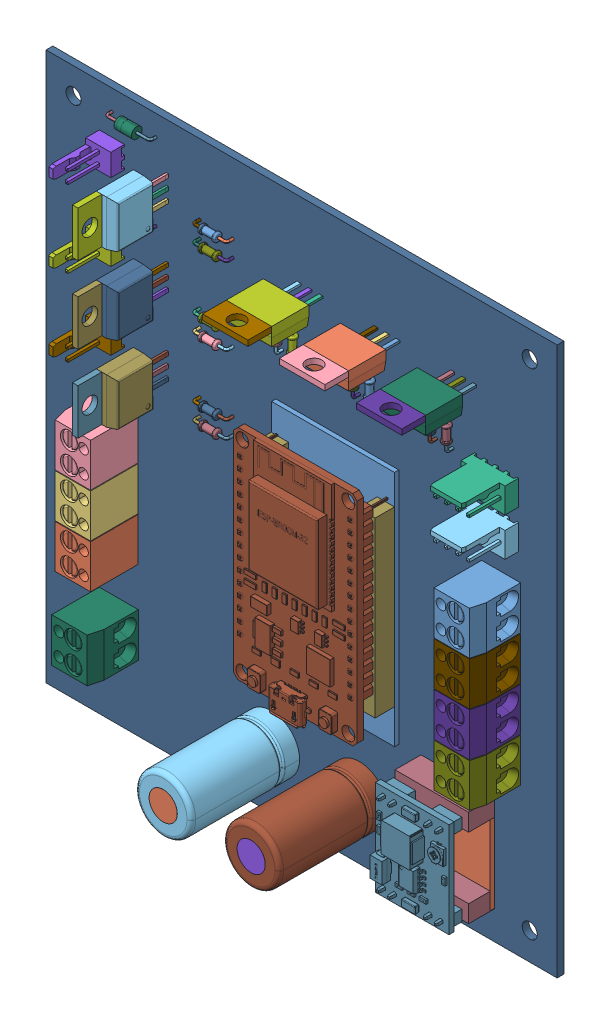
SolidWorks assembly ESP pcb v2 cad, configuration Standard. Lengths in mm.
Overall size (118.09 126.67 29.51).
107 component instances, 104 part files, 12 mates.
Components (placement in the parent):
- PPP5efa1a2bd6d06.stp-1: PPP5efa1a2bd6d06.stp [Standard] at origin size (118.09 126.67 29.51)
  - CAPPRD500W45D1300H2500P001.stp-1: CAPPRD500W45D1300H2500P001.stp [Standard] at (80.01 45.72 1.57) x (0 1 0) z (0 0 1) size (0.45 0.45 2.54)
  - CAPPRD500W45D1300H2500P002.stp-1: CAPPRD500W45D1300H2500P002.stp [Standard] at (80.01 45.72 1.57) x (0 1 0) z (0 0 1) size (6.5 6.5 0.01)
  - CAPPRD500W45D1300H2500P003.stp-1: CAPPRD500W45D1300H2500P003.stp [Standard] at (80.01 45.72 1.57) x (0 1 0) z (0 0 1) size (0.62 5.51 19.3)
  - CAPPRD500W45D1300H2500P004.stp-1: CAPPRD500W45D1300H2500P004.stp [Standard] at (80.01 45.72 1.57) x (0 1 0) z (0 0 1) size (0.62 5.51 3.3)
  - CAPPRD500W45D1300H2500P005.stp-1: CAPPRD500W45D1300H2500P005.stp [Standard] at (80.01 45.72 1.57) x (0 1 0) z (0 0 1) size (13 13 25)
  - CAPPRD500W45D1300H2500P.stp-1: CAPPRD500W45D1300H2500P.stp [Standard] at (80.01 45.72 1.57) x (0 1 0) z (0 0 1) size (0.45 0.45 2.54)
  - CAPPRD500W45D1300H2500P006.stp-1: CAPPRD500W45D1300H2500P006.stp [Standard] at (100.33 45.72 1.57) x (0 1 0) z (0 0 1) size (0.45 0.45 2.54)
  - CAPPRD500W45D1300H2500P007.stp-1: CAPPRD500W45D1300H2500P007.stp [Standard] at (100.33 45.72 1.57) x (0 1 0) z (0 0 1) size (6.5 6.5 0.01)
  - CAPPRD500W45D1300H2500P008.stp-1: CAPPRD500W45D1300H2500P008.stp [Standard] at (100.33 45.72 1.57) x (0 1 0) z (0 0 1) size (0.62 5.51 19.3)
  - CAPPRD500W45D1300H2500P009.stp-1: CAPPRD500W45D1300H2500P009.stp [Standard] at (100.33 45.72 1.57) x (0 1 0) z (0 0 1) size (0.62 5.51 3.3)
  - CAPPRD500W45D1300H2500P010.stp-1: CAPPRD500W45D1300H2500P010.stp [Standard] at (100.33 45.72 1.57) x (0 1 0) z (0 0 1) size (13 13 25)
  - CAPPRD500W45D1300H2500P011.stp-1: CAPPRD500W45D1300H2500P011.stp [Standard] at (100.33 45.72 1.57) x (0 1 0) z (0 0 1) size (0.45 0.45 2.54)
  - DIOAD1016W58L400D250P.stp-1: DIOAD1016W58L400D250P.stp [Standard] at (48.26 153.67 1.57) size (3.37 0.58 4.18)
  - DIOAD1016W58L400D250P001.stp-1: DIOAD1016W58L400D250P001.stp [Standard] at (48.26 153.67 1.57) size (3.37 0.58 4.18)
  - DIOAD1016W58L400D250P002.stp-1: DIOAD1016W58L400D250P002.stp [Standard] at (48.26 153.67 1.57) size (4 2.51 2.51)
  - DIOAD1016W58L400D250P003.stp-1: DIOAD1016W58L400D250P003.stp [Standard] at (48.26 135.89 1.57) size (3.37 0.58 4.18)
  - DIOAD1016W58L400D250P004.stp-1: DIOAD1016W58L400D250P004.stp [Standard] at (48.26 135.89 1.57) size (3.37 0.58 4.18)
  - DIOAD1016W58L400D250P005.stp-1: DIOAD1016W58L400D250P005.stp [Standard] at (48.26 135.89 1.57) size (4 2.51 2.51)
  - Component_1.stp-1: Component_1.stp [Standard] at (95.25 87.63 1.57) x (-1 0 0) z (0 0 1) size (28.4 54.9 1)
  - Component_2.stp-1: Component_2.stp [Standard] at (123.19 49.53 1.57) x (0 1 0) z (0 0 1) size (22.1 16.76 1)
  - TO254P1051X465X1957-3P.stp-1: TO254P1051X465X1957-3P.stp [Standard] at (53.34 144.78 1.57) x (0 1 0) z (0 0 1) size (0.9 0.49 5.51)
  - TO254P1051X465X1957-3P002.stp-1: TO254P1051X465X1957-3P002.stp [Standard] at (53.34 144.78 1.57) x (0 1 0) z (0 0 1) size (0.9 0.49 5.51)
  - TO254P1051X465X1957-3P004.stp-1: TO254P1051X465X1957-3P004.stp [Standard] at (53.34 144.78 1.57) x (0 1 0) z (0 0 1) size (13.23 6.47 11.63)
  - TO254P1051X465X1957-3P001.stp-1: TO254P1051X465X1957-3P001.stp [Standard] at (53.34 144.78 1.57) x (0 1 0) z (0 0 1) size (0.9 0.49 5.51)
  - TO254P1051X465X1957-3P003.stp-1: TO254P1051X465X1957-3P003.stp [Standard] at (53.34 144.78 1.57) x (0 1 0) z (0 0 1) size (10.51 1.27 5.5)
  - TO254P1051X465X1957-3P005.stp-1: TO254P1051X465X1957-3P005.stp [Standard] at (53.34 127 1.57) x (0 1 0) z (0 0 1) size (0.9 0.49 5.51)
  - TO254P1051X465X1957-3P006.stp-1: TO254P1051X465X1957-3P006.stp [Standard] at (53.34 127 1.57) x (0 1 0) z (0 0 1) size (0.9 0.49 5.51)
  - TO254P1051X465X1957-3P007.stp-1: TO254P1051X465X1957-3P007.stp [Standard] at (53.34 127 1.57) x (0 1 0) z (0 0 1) size (13.23 6.47 11.63)
  - TO254P1051X465X1957-3P008.stp-1: TO254P1051X465X1957-3P008.stp [Standard] at (53.34 127 1.57) x (0 1 0) z (0 0 1) size (0.9 0.49 5.51)
  - TO254P1051X465X1957-3P009.stp-1: TO254P1051X465X1957-3P009.stp [Standard] at (53.34 127 1.57) x (0 1 0) z (0 0 1) size (10.51 1.27 5.5)
  - TO254P1051X465X1957-3P010.stp-1: TO254P1051X465X1957-3P010.stp [Standard] at (124.46 143.51 1.57) size (0.9 0.49 5.51)
  - TO254P1051X465X1957-3P011.stp-1: TO254P1051X465X1957-3P011.stp [Standard] at (124.46 143.51 1.57) size (0.9 0.49 5.51)
  - TO254P1051X465X1957-3P012.stp-1: TO254P1051X465X1957-3P012.stp [Standard] at (124.46 143.51 1.57) size (13.23 6.47 11.63)
  - TO254P1051X465X1957-3P013.stp-1: TO254P1051X465X1957-3P013.stp [Standard] at (124.46 143.51 1.57) size (0.9 0.49 5.51)
  - TO254P1051X465X1957-3P014.stp-1: TO254P1051X465X1957-3P014.stp [Standard] at (124.46 143.51 1.57) size (10.51 1.27 5.5)
  - TO254P1051X465X1957-3P015.stp-1: TO254P1051X465X1957-3P015.stp [Standard] at (106.68 143.51 1.57) size (0.9 0.49 5.51)
  - TO254P1051X465X1957-3P016.stp-1: TO254P1051X465X1957-3P016.stp [Standard] at (106.68 143.51 1.57) size (0.9 0.49 5.51)
  - TO254P1051X465X1957-3P017.stp-1: TO254P1051X465X1957-3P017.stp [Standard] at (106.68 143.51 1.57) size (13.23 6.47 11.63)
  - TO254P1051X465X1957-3P018.stp-1: TO254P1051X465X1957-3P018.stp [Standard] at (106.68 143.51 1.57) size (0.9 0.49 5.51)
  - TO254P1051X465X1957-3P019.stp-1: TO254P1051X465X1957-3P019.stp [Standard] at (106.68 143.51 1.57) size (10.51 1.27 5.5)
  - TO254P1051X465X1957-3P020.stp-1: TO254P1051X465X1957-3P020.stp [Standard] at (88.9 143.51 1.57) size (0.9 0.49 5.51)
  - TO254P1051X465X1957-3P021.stp-1: TO254P1051X465X1957-3P021.stp [Standard] at (88.9 143.51 1.57) size (0.9 0.49 5.51)
  - TO254P1051X465X1957-3P022.stp-1: TO254P1051X465X1957-3P022.stp [Standard] at (88.9 143.51 1.57) size (13.23 6.47 11.63)
  - TO254P1051X465X1957-3P023.stp-1: TO254P1051X465X1957-3P023.stp [Standard] at (88.9 143.51 1.57) size (0.9 0.49 5.51)
  - TO254P1051X465X1957-3P024.stp-1: TO254P1051X465X1957-3P024.stp [Standard] at (88.9 143.51 1.57) size (10.51 1.27 5.5)
  - TO254P1051X465X1957-3P025.stp-1: TO254P1051X465X1957-3P025.stp [Standard] at (53.34 109.22 1.57) x (0 1 0) z (0 0 1) size (0.9 0.49 5.51)
  - TO254P1051X465X1957-3P026.stp-1: TO254P1051X465X1957-3P026.stp [Standard] at (53.34 109.22 1.57) x (0 1 0) z (0 0 1) size (0.9 0.49 5.51)
  - TO254P1051X465X1957-3P027.stp-1: TO254P1051X465X1957-3P027.stp [Standard] at (53.34 109.22 1.57) x (0 1 0) z (0 0 1) size (13.23 6.47 11.63)
  - TO254P1051X465X1957-3P028.stp-1: TO254P1051X465X1957-3P028.stp [Standard] at (53.34 109.22 1.57) x (0 1 0) z (0 0 1) size (0.9 0.49 5.51)
  - TO254P1051X465X1957-3P029.stp-1: TO254P1051X465X1957-3P029.stp [Standard] at (53.34 109.22 1.57) x (0 1 0) z (0 0 1) size (10.51 1.27 5.5)
  - RESAD762W60L400D200P001.stp-1: RESAD762W60L400D200P001.stp [Standard] at (67.31 138.43 1.57) x (-1 0 0) z (0 0 1) size (2.11 0.6 1.8)
  - RESAD762W60L400D200P002.stp-1: RESAD762W60L400D200P002.stp [Standard] at (67.31 138.43 1.57) x (-1 0 0) z (0 0 1) size (4 2 2)
  - RESAD762W60L400D200P.stp-1: RESAD762W60L400D200P.stp [Standard] at (67.31 138.43 1.57) x (-1 0 0) z (0 0 1) size (2.11 0.6 1.8)
  - RESAD762W60L400D200P003.stp-1: RESAD762W60L400D200P003.stp [Standard] at (67.31 142.24 1.57) x (-1 0 0) z (0 0 1) size (2.11 0.6 1.8)
  - RESAD762W60L400D200P004.stp-1: RESAD762W60L400D200P004.stp [Standard] at (67.31 142.24 1.57) x (-1 0 0) z (0 0 1) size (4 2 2)
  - RESAD762W60L400D200P005.stp-1: RESAD762W60L400D200P005.stp [Standard] at (67.31 142.24 1.57) x (-1 0 0) z (0 0 1) size (2.11 0.6 1.8)
  - RESAD762W60L400D200P006.stp-1: RESAD762W60L400D200P006.stp [Standard] at (67.31 120.65 1.57) x (-1 0 0) z (0 0 1) size (2.11 0.6 1.8)
  - RESAD762W60L400D200P007.stp-1: RESAD762W60L400D200P007.stp [Standard] at (67.31 120.65 1.57) x (-1 0 0) z (0 0 1) size (4 2 2)
  - RESAD762W60L400D200P008.stp-1: RESAD762W60L400D200P008.stp [Standard] at (67.31 120.65 1.57) x (-1 0 0) z (0 0 1) size (2.11 0.6 1.8)
  - RESAD762W60L400D200P009.stp-1: RESAD762W60L400D200P009.stp [Standard] at (67.31 124.46 1.57) x (-1 0 0) z (0 0 1) size (2.11 0.6 1.8)
  - RESAD762W60L400D200P010.stp-1: RESAD762W60L400D200P010.stp [Standard] at (67.31 124.46 1.57) x (-1 0 0) z (0 0 1) size (4 2 2)
  - RESAD762W60L400D200P011.stp-1: RESAD762W60L400D200P011.stp [Standard] at (67.31 124.46 1.57) x (-1 0 0) z (0 0 1) size (2.11 0.6 1.8)
  - RESAD762W60L400D200P012.stp-1: RESAD762W60L400D200P012.stp [Standard] at (118.11 129.54 1.57) x (0 1 0) z (0 0 1) size (2.11 0.6 1.8)
  - RESAD762W60L400D200P013.stp-1: RESAD762W60L400D200P013.stp [Standard] at (118.11 129.54 1.57) x (0 1 0) z (0 0 1) size (4 2 2)
  - RESAD762W60L400D200P014.stp-1: RESAD762W60L400D200P014.stp [Standard] at (118.11 129.54 1.57) x (0 1 0) z (0 0 1) size (2.11 0.6 1.8)
  - RESAD762W60L400D200P015.stp-1: RESAD762W60L400D200P015.stp [Standard] at (121.92 129.54 1.57) x (0 1 0) z (0 0 1) size (2.11 0.6 1.8)
  - RESAD762W60L400D200P016.stp-1: RESAD762W60L400D200P016.stp [Standard] at (121.92 129.54 1.57) x (0 1 0) z (0 0 1) size (4 2 2)
  - RESAD762W60L400D200P017.stp-1: RESAD762W60L400D200P017.stp [Standard] at (121.92 129.54 1.57) x (0 1 0) z (0 0 1) size (2.11 0.6 1.8)
  - RESAD762W60L400D200P018.stp-1: RESAD762W60L400D200P018.stp [Standard] at (100.33 129.54 1.57) x (0 1 0) z (0 0 1) size (2.11 0.6 1.8)
  - RESAD762W60L400D200P019.stp-1: RESAD762W60L400D200P019.stp [Standard] at (100.33 129.54 1.57) x (0 1 0) z (0 0 1) size (4 2 2)
  - RESAD762W60L400D200P020.stp-1: RESAD762W60L400D200P020.stp [Standard] at (100.33 129.54 1.57) x (0 1 0) z (0 0 1) size (2.11 0.6 1.8)
  - RESAD762W60L400D200P021.stp-1: RESAD762W60L400D200P021.stp [Standard] at (104.14 129.54 1.57) x (0 1 0) z (0 0 1) size (2.11 0.6 1.8)
  - RESAD762W60L400D200P022.stp-1: RESAD762W60L400D200P022.stp [Standard] at (104.14 129.54 1.57) x (0 1 0) z (0 0 1) size (4 2 2)
  - RESAD762W60L400D200P023.stp-1: RESAD762W60L400D200P023.stp [Standard] at (104.14 129.54 1.57) x (0 1 0) z (0 0 1) size (2.11 0.6 1.8)
  - RESAD762W60L400D200P024.stp-1: RESAD762W60L400D200P024.stp [Standard] at (82.55 129.54 1.57) x (0 1 0) z (0 0 1) size (2.11 0.6 1.8)
  - RESAD762W60L400D200P025.stp-1: RESAD762W60L400D200P025.stp [Standard] at (82.55 129.54 1.57) x (0 1 0) z (0 0 1) size (4 2 2)
  - RESAD762W60L400D200P026.stp-1: RESAD762W60L400D200P026.stp [Standard] at (82.55 129.54 1.57) x (0 1 0) z (0 0 1) size (2.11 0.6 1.8)
  - RESAD762W60L400D200P027.stp-1: RESAD762W60L400D200P027.stp [Standard] at (86.36 129.54 1.57) x (0 1 0) z (0 0 1) size (2.11 0.6 1.8)
  - RESAD762W60L400D200P028.stp-1: RESAD762W60L400D200P028.stp [Standard] at (86.36 129.54 1.57) x (0 1 0) z (0 0 1) size (4 2 2)
  - RESAD762W60L400D200P029.stp-1: RESAD762W60L400D200P029.stp [Standard] at (86.36 129.54 1.57) x (0 1 0) z (0 0 1) size (2.11 0.6 1.8)
  - RESAD762W60L400D200P030.stp-1: RESAD762W60L400D200P030.stp [Standard] at (67.31 106.68 1.57) x (-1 0 0) z (0 0 1) size (2.11 0.6 1.8)
  - RESAD762W60L400D200P031.stp-1: RESAD762W60L400D200P031.stp [Standard] at (67.31 106.68 1.57) x (-1 0 0) z (0 0 1) size (4 2 2)
  - RESAD762W60L400D200P032.stp-1: RESAD762W60L400D200P032.stp [Standard] at (67.31 106.68 1.57) x (-1 0 0) z (0 0 1) size (2.11 0.6 1.8)
  - RESAD762W60L400D200P033.stp-1: RESAD762W60L400D200P033.stp [Standard] at (67.31 102.87 1.57) x (-1 0 0) z (0 0 1) size (2.11 0.6 1.8)
  - RESAD762W60L400D200P034.stp-1: RESAD762W60L400D200P034.stp [Standard] at (67.31 102.87 1.57) x (-1 0 0) z (0 0 1) size (4 2 2)
  - RESAD762W60L400D200P035.stp-1: RESAD762W60L400D200P035.stp [Standard] at (67.31 102.87 1.57) x (-1 0 0) z (0 0 1) size (2.11 0.6 1.8)
  - HI_237-132.stp-1: HI_237-132.stp [Standard] at (44.45 52.07 1.57) x (0 1 0) z (0 0 1) size (10.16 9 15.5)
  - HI_237-102.stp-1: HI_237-102.stp [Standard] at (132.08 71.12 1.57) x (0 1 0) z (0 0 1) size (10 9 15.5)
  - HI_237-133.stp-1: HI_237-133.stp [Standard] at (132.08 81.28 1.57) x (0 1 0) z (0 0 1) size (10 9 15.5)
  - HI_237-134.stp-1: HI_237-134.stp [Standard] at (132.08 91.44 1.57) x (0 1 0) z (0 0 1) size (10 9 15.5)
  - HI_237-135.stp-1: HI_237-135.stp [Standard] at (132.08 101.6 1.57) x (0 1 0) z (0 0 1) size (10 9 15.5)
  - HI_237-136.stp-1: HI_237-136.stp [Standard] at (45.72 71.12 1.57) x (0 -1 0) z (0 0 1) size (10 9 15.5)
  - HI_237-137.stp-1: HI_237-137.stp [Standard] at (45.72 81.28 1.57) x (0 -1 0) z (0 0 1) size (10 9 15.5)
  - HI_237-138.stp-1: HI_237-138.stp [Standard] at (45.72 91.44 1.57) x (0 -1 0) z (0 0 1) size (10 9 15.5)
  - =_[0_1_1_2].stp-1: =_[0_1_1_2].stp [Standard] at (132.08 115.57 1.57) size (10.16 5.8 15.26)
  - =_[0_1_1_2]001.stp-1: =_[0_1_1_2]001.stp [Standard] at (132.08 124.46 1.57) size (10.16 5.8 15.26)
  - =_[0_1_1_2]002.stp-1: =_[0_1_1_2]002.stp [Standard] at (43.18 128.27 1.57) x (0 1 0) z (0 0 1) size (5.08 5.8 15.26)
  - =_[0_1_1_2]003.stp-1: =_[0_1_1_2]003.stp [Standard] at (43.18 146.05 1.57) x (0 1 0) z (0 0 1) size (5.08 5.8 15.26)
  - =_[0_1_1_2]004.stp-1: =_[0_1_1_2]004.stp [Standard] at (43.18 110.49 1.57) x (0 1 0) z (0 0 1) size (5.08 5.8 15.26)
  - Component_Component.stp-1: Component_Component.stp [Standard] at origin size (118.09 126.67 1.57)
- ESP-WROOM32-2: ESP-WROOM32 [Standard] at (96.526 74.2599 12.3089) x (1 0 0) z (0 -1 0) size (28.5 12.4 50.93)
- Pin header female-1: Pin header female [Standard] at (105.45 108.23 1.57) x (1 0 0) z (0 -1 0) size (4 5.5 40)
- Pin header female-2: Pin header female [Standard] at (80.9595 108.93 1.6125) x (1 0 0) z (0 -1 0) size (4 5.5 40)
- female header small-2: female header small [Standard] at (131.572 42.381 1.57) x (0 -1 0) z (-1 0 0) size (4 6 17)
- female header small-3: female header small [Standard] at (114.572 56.679 1.57) x (0 1 0) z (1 0 0) size (4 6 17)
- User Library-MP1584EN-1: User Library-MP1584EN [Default] at (115.6421 39.4509 11.3123) x (0 1 0) z (0 0 1) size (22 17 12.64)
Mates (geometry in assembly coordinates):
- Deckungsgleich1: coincident anti-aligned: line of PPP5efa1a2bd6d06.stp-1/Component_1.stp-1 through (109.45 115.13 1.57) axis (0 -1 0); line of Pin header female-1 through (109.45 68.23 1.57) axis (0 1 0)
- Abstand1: distance = 8 mm aligned: plane of Pin header female-1 through (105.45 68.23 1.57) normal (0 -1 0); plane of PPP5efa1a2bd6d06.stp-1/Component_1.stp-1 through (109.45 60.23 1.57) normal (0 -1 0)
- Abstand2: distance = 0.1 mm: line of Pin header female-2 through (80.9595 68.93 1.6125) axis (0 1 0); line of PPP5efa1a2bd6d06.stp-1/Component_1.stp-1 through (81.05 60.23 1.57) axis (0 1 0)
- Deckungsgleich5: coincident anti-aligned: line of ESP-WROOM32-2 through (80.9595 86.9649 7.1125) axis (0 -1 0); line of Pin header female-2 through (80.9595 68.93 7.1125) axis (0 1 0)
- Deckungsgleich6: coincident anti-aligned: plane of PPP5efa1a2bd6d06.stp-1/Component_Component.stp-1 through (27.94 31.75 1.57) normal (0 0 1); plane of female header small-2 through (114.572 42.381 1.57) normal (0 0 -1)
- Abstand4: distance = 0.1 mm: line of female header small-2 through (114.572 38.381 1.57) axis (1 0 0); line of PPP5efa1a2bd6d06.stp-1/Component_2.stp-1 through (131.572 38.481 1.57) axis (-1 0 0)
- Deckungsgleich9: coincident aligned: line of PPP5efa1a2bd6d06.stp-1/Component_2.stp-1 through (131.572 60.579 1.57) axis (0 -1 0); line of female header small-2 through (131.572 42.381 1.57) axis (0 -1 0)
- Deckungsgleich10: coincident anti-aligned: plane of PPP5efa1a2bd6d06.stp-1/Component_Component.stp-1 through (27.94 31.75 1.57) normal (0 0 1); plane of female header small-3 through (131.572 56.679 1.57) normal (0 0 -1)
- Abstand5: distance = 0.1 mm: line of female header small-3 through (131.572 60.679 1.57) axis (-1 0 0); line of PPP5efa1a2bd6d06.stp-1/Component_2.stp-1 through (114.808 60.579 1.57) axis (1 0 0)
- Deckungsgleich12: coincident anti-aligned: line of PPP5efa1a2bd6d06.stp-1/Component_2.stp-1 through (131.572 60.579 1.57) axis (0 -1 0); line of female header small-3 through (131.572 56.679 1.57) axis (0 1 0)
- Deckungsgleich17: coincident: line of female header small-2 through (114.572 38.381 7.57) axis (1 0 0); line of User Library-MP1584EN-1 through (116.4706 38.381 7.57) axis (1 0 0)
- Deckungsgleich18: coincident: line of female header small-2 through (114.572 38.381 7.57) axis (0 1 0); plane of User Library-MP1584EN-1 through (114.372 40.721 7.77) normal (-0.707107 0 -0.707107)
